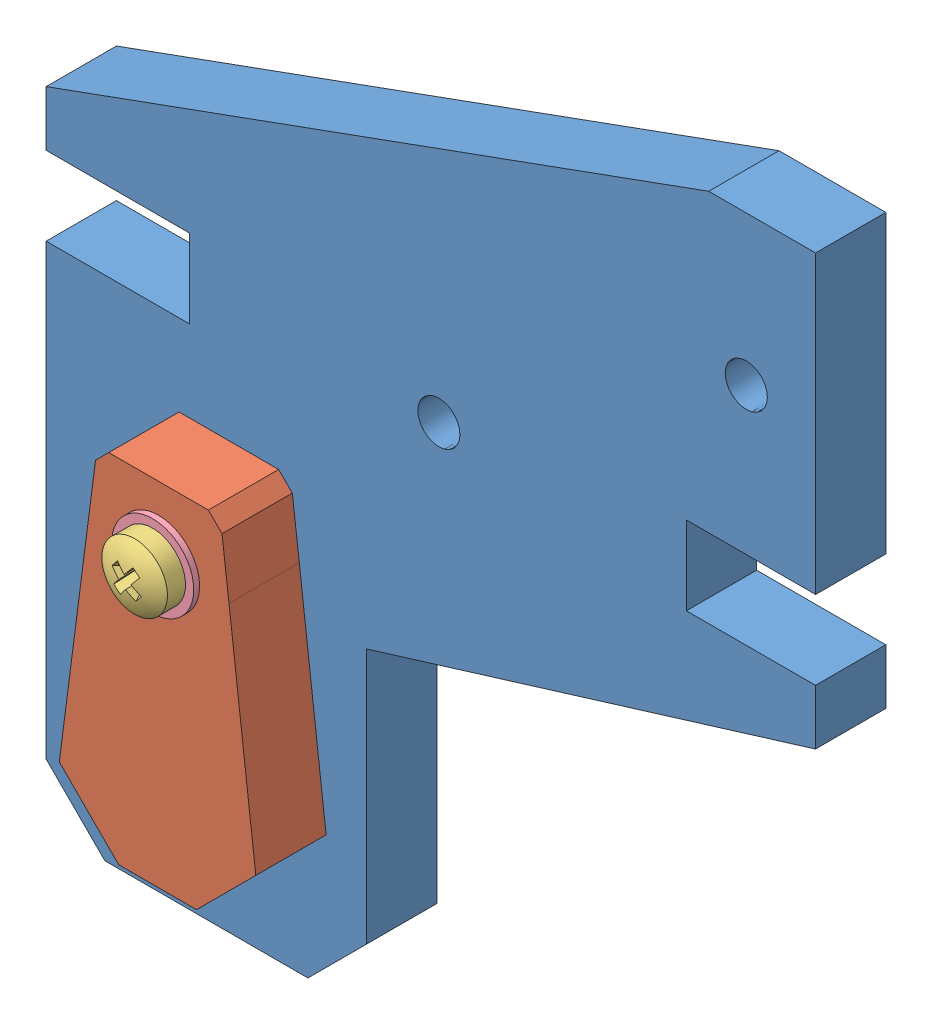
SolidWorks assembly Assembly Z-Top Left, configuration Valor predeterminado. Lengths in mm.
Overall size (65.68 75.26 18.37).
7 component instances, 5 part files, 12 mates.
Components (placement in the parent):
- Z-Top-1: Z-Top [Valor predeterminado] at (-60.5517 37.2517 6) x (1 0 0) z (0 0 -1) size (65.68 75.26 6)
- Z-Smooth Rod Constraint-1: Z-Smooth Rod Constraint [Valor predeterminado] at (-57.9192 -51.9169 6) size (16.77 30.05 6)
- Assembly Screw DIN 7985 - M3 x 16 --- 16N + Washer DIN 125A - M3-1: Assembly Screw DIN 7985 - M3 x 16 --- 16N + Washer DIN 125A - M3 [Valor predeterminado] at (-29.4552 -30.5598 8.6091) x (0 0 1) z (0.627668 0.778481 0) size (18.37 7 7)
  - Screw DIN 7985 - M3 x 16 --- 16N-1: Screw DIN 7985 - M3 x 16 --- 16N [Valor predeterminado] at (6.2909 0.1077 18.3725) size (18.37 5.6 5.6)
  - Washer DIN 125A - M3-1: Washer DIN 125A - M3 [Valor predeterminado] at (3.3909 0.1077 18.3725) size (0.5 7 7)
- Nut DIN 934 - M3-1: Nut DIN 934 - M3 [Valor predeterminado] at (-17.8395 -16.3247 -1.2) x (0 0 1) z (-0.962012 0.273008 0) size (2.4 5.5 6.35)
- Washer DIN 125A - M3-1: Washer DIN 125A - M3 [Valor predeterminado] at (-17.8395 -16.3247 -0.5) x (0 0 1) z (-0.942258 -0.334889 0) size (0.5 7 7)
Mates (geometry in assembly coordinates):
- Coincidente1: coincident: plane of assembly through (0 0 0) normal (0 0 1); plane of Z-Top-1 through (-60.5517 37.2517 0) normal (0 0 -1); plane of assembly
- Simétrico1: symmetric: plane of assembly; plane of assembly; plane of Z-Top-1 through (21.2131 3.3573 0) normal (0 -1 0); plane of Z-Top-1 through (32.2356 -3.3573 0) normal (0 1 0); plane of assembly
- Simétrico2: symmetric: plane of assembly; plane of assembly; plane of Z-Top-1 through (21.2131 -3.3573 0) normal (1 0 0); plane of Z-Top-1 through (-21.2131 3.3573 0) normal (-1 0 0); plane of assembly
- Concêntrico1: concentric: cylinder of assembly; cylinder of assembly; cylinder of Z-Top-1 through (-17.8395 -16.3247 0) axis (0 0 1) radius 1.8; cylinder of Z-Smooth Rod Constraint-1 through (-17.8395 -16.3247 12) axis (0 0 -1) radius 1.8
- Coincidente2: coincident: plane of assembly; plane of assembly; plane of Z-Top-1 through (-60.5517 37.2517 6) normal (0 0 1); plane of Z-Smooth Rod Constraint-1 through (-57.9192 -51.9169 6) normal (0 0 -1)
- Paralelo2: parallel: plane of assembly; plane of Z-Smooth Rod Constraint-1 through (-13.5883 -10.3112 12) normal (0 1 0); plane of assembly
- Concêntrico2: concentric: cylinder of assembly; cylinder of assembly; cylinder of Z-Smooth Rod Constraint-1 through (-17.8395 -16.3247 12) axis (0 0 -1) radius 1.8; cylinder of Assembly Screw DIN 7985 - M3 x 16 --- 16N + Washer DIN 125A - M3-1/Screw DIN 7985 - M3 x 16 --- 16N-1 through (-17.8395 -16.3247 14.9) axis (0 0 1) radius 1.5
- Coincidente3: coincident: plane of Z-Smooth Rod Constraint-1 through (-57.9192 -51.9169 12) normal (0 0 1); plane of Assembly Screw DIN 7985 - M3 x 16 --- 16N + Washer DIN 125A - M3-1/Washer DIN 125A - M3-1 through (-17.8395 -16.3247 12) normal (0 0 -1)
- Coincidente4: coincident: plane of assembly; plane of assembly; plane of Z-Top-1 through (-60.5517 37.2517 0) normal (0 0 -1); plane of Washer DIN 125A - M3-1 through (-17.8395 -16.3247 0) normal (0 0 1)
- Concêntrico3: concentric: cylinder of assembly; cylinder of assembly; cylinder of Assembly Screw DIN 7985 - M3 x 16 --- 16N + Washer DIN 125A - M3-1/Screw DIN 7985 - M3 x 16 --- 16N-1 through (-17.8395 -16.3247 14.9) axis (0 0 1) radius 1.5; cylinder of Washer DIN 125A - M3-1 through (-17.8395 -16.3247 0) axis (0 0 -1) radius 1.6
- Concêntrico4: concentric: cylinder of assembly; cylinder of assembly; cylinder of Assembly Screw DIN 7985 - M3 x 16 --- 16N + Washer DIN 125A - M3-1/Screw DIN 7985 - M3 x 16 --- 16N-1 through (-17.8395 -16.3247 14.9) axis (0 0 1) radius 1.5; cylinder of Nut DIN 934 - M3-1 through (-17.8395 -16.3247 0) axis (0 0 -1) radius 1.25
- Coincidente5: coincident: plane of assembly; plane of assembly; plane of Z-Top-1 through (-60.5517 37.2517 0) normal (0 0 -1); plane of Nut DIN 934 - M3-1 through (-17.0629 -19.4037 0) normal (0 0 1)
